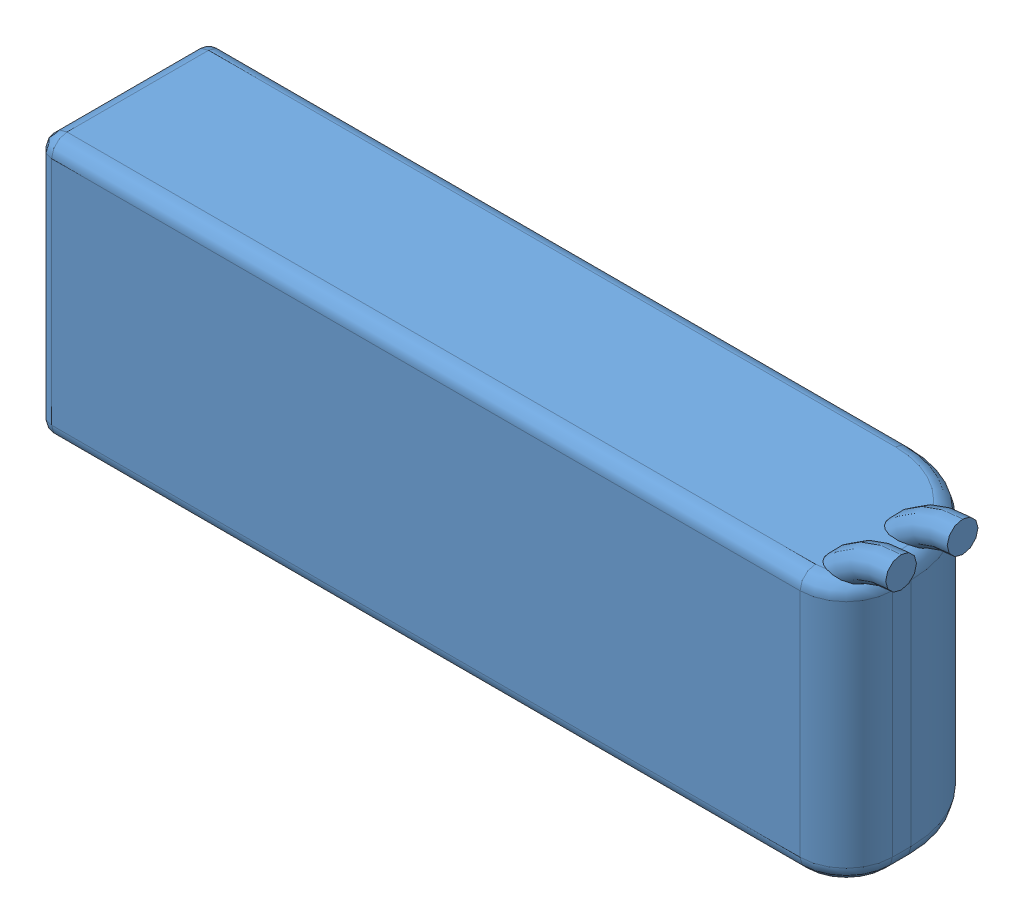
SolidWorks assembly BatteryAssembly, configuration Default. Lengths in mm.
Overall size (137.69 49.07 28.45).
3 component instances, 1 part files, 10 mates.
Components (placement in the parent):
- Battery-1: Battery [Default] at (14.2695 29.21 28.448) x (1 0 0) z (0 1 0) size (137.69 28.45 49.07)
- Bolt^BatteryAssembly-1: Bolt^BatteryAssembly [Default] at (37.1091 0.4828 -2.3813) x (0.5 0 -0.866025) z (0 -1 0) (suppressed, hidden, virtual)
- Bolt^BatteryAssembly-2: Bolt^BatteryAssembly [Default] at (96.6091 0.4828 -2.3813) x (0.5 0 -0.866025) z (0 -1 0) (suppressed, hidden, virtual)
Mates (geometry in assembly coordinates):
- Coincident10: coincident anti-aligned: circle of Bolt^BatteryAssembly-1/92141A003_18-8 Stainless Steel Washer-1; plane of Bolt^BatteryAssembly-2/92141A003_18-8 Stainless Steel Washer-1 through (121.0183 32.5628 30.9713) normal (0 1 0)
- Coincident14: coincident anti-aligned: plane of Bolt^BatteryAssembly-1/91780A039_Female Threaded Hex Standoff-1 through (39.8588 0 -2.3813) normal (0 -1 0)
- Coincident24: coincident aligned: plane of Bolt^BatteryAssembly-1/91780A039_Female Threaded Hex Standoff-1 through (39.8588 50.8 -2.3813) normal (0 1 0); plane of Bolt^BatteryAssembly-2/91780A039_Female Threaded Hex Standoff-1 through (99.3588 50.8 -2.3813) normal (0 1 0)
- Distance6: distance = 59.5 mm: point of Bolt^BatteryAssembly-2/91251A077_Black-Oxide Alloy Steel Socket Head Screw-3; point of Bolt^BatteryAssembly-1/91251A077_Black-Oxide Alloy Steel Socket Head Screw-3
- Coincident31: coincident anti-aligned: plane of Bolt^BatteryAssembly-2/91780A039_Female Threaded Hex Standoff-1 through (99.3588 0 -2.3813) normal (0 -1 0)
- Coincident32: coincident anti-aligned: plane of Battery-1 through (14.2695 50.8 0) normal (0 0 -1)
- Coincident33: coincident anti-aligned: plane of Battery-1 through (14.2695 50.8 0) normal (0 0 -1); plane of Bolt^BatteryAssembly-1/91780A039_Female Threaded Hex Standoff-1 through (38.484 0 0) normal (0 0 1)
- Coincident34: coincident anti-aligned: plane of Battery-1 through (14.2695 50.8 0) normal (0 0 -1); plane of Bolt^BatteryAssembly-2/91780A039_Female Threaded Hex Standoff-1 through (97.984 0 0) normal (0 0 1)
- Distance7: distance = 50.8 mm anti-aligned: plane of Battery-1 through (14.2695 50.8 28.448) normal (0 1 0); plane of Bolt^BatteryAssembly-2/91780A039_Female Threaded Hex Standoff-1 through (99.3588 0 -2.3813) normal (0 -1 0)
- Distance8: distance = 37.1091 mm: point of assembly; plane of assembly; point of Bolt^BatteryAssembly-1/91251A077_Black-Oxide Alloy Steel Socket Head Screw-1
